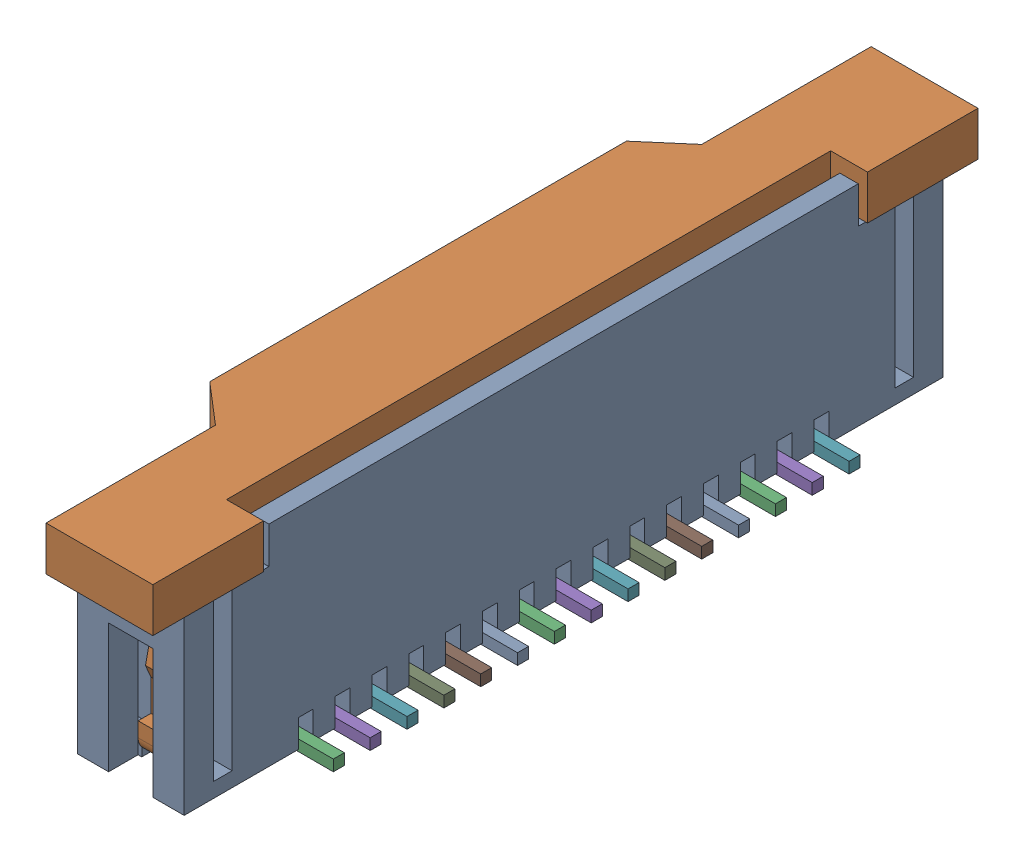
SolidWorks assembly raspberry_pi__15_pin_FFC_Connector, configuration Default. Lengths in mm.
Overall size (4.85 6 22.4).
17 component instances, 3 part files, 0 mates.
Components (placement in the parent):
- raspberry_pi__15_pin_FFC_Connector_body-1: raspberry_pi__15_pin_FFC_Connector_body [Default] at (-100.5372 19.1242 0) size (2.9 5.7 20.6)
- raspberry_pi__15_pin_FFC_Connector_locker-1: raspberry_pi__15_pin_FFC_Connector_locker [Default] at (-101.0372 23.8242 0) size (4 5.4 22.4)
- raspberry_pi__15_pin_FFC_Connector_pins-1: raspberry_pi__15_pin_FFC_Connector_pins [Default] at (-100.5372 19.1242 7.15) x (-1 0 0) z (0 0 -1) size (4.3 4.71 0.3)
- raspberry_pi__15_pin_FFC_Connector_pins-2: raspberry_pi__15_pin_FFC_Connector_pins [Default] at (-100.5372 19.1242 6.15) x (-1 0 0) z (0 0 -1) size (4.3 4.71 0.3)
- raspberry_pi__15_pin_FFC_Connector_pins-3: raspberry_pi__15_pin_FFC_Connector_pins [Default] at (-100.5372 19.1242 5.15) x (-1 0 0) z (0 0 -1) size (4.3 4.71 0.3)
- raspberry_pi__15_pin_FFC_Connector_pins-4: raspberry_pi__15_pin_FFC_Connector_pins [Default] at (-100.5372 19.1242 4.15) x (-1 0 0) z (0 0 -1) size (4.3 4.71 0.3)
- raspberry_pi__15_pin_FFC_Connector_pins-5: raspberry_pi__15_pin_FFC_Connector_pins [Default] at (-100.5372 19.1242 3.15) x (-1 0 0) z (0 0 -1) size (4.3 4.71 0.3)
- raspberry_pi__15_pin_FFC_Connector_pins-6: raspberry_pi__15_pin_FFC_Connector_pins [Default] at (-100.5372 19.1242 2.15) x (-1 0 0) z (0 0 -1) size (4.3 4.71 0.3)
- raspberry_pi__15_pin_FFC_Connector_pins-7: raspberry_pi__15_pin_FFC_Connector_pins [Default] at (-100.5372 19.1242 1.15) x (-1 0 0) z (0 0 -1) size (4.3 4.71 0.3)
- raspberry_pi__15_pin_FFC_Connector_pins-8: raspberry_pi__15_pin_FFC_Connector_pins [Default] at (-100.5372 19.1242 0.15) x (-1 0 0) z (0 0 -1) size (4.3 4.71 0.3)
- raspberry_pi__15_pin_FFC_Connector_pins-9: raspberry_pi__15_pin_FFC_Connector_pins [Default] at (-100.5372 19.1242 -0.85) x (-1 0 0) z (0 0 -1) size (4.3 4.71 0.3)
- raspberry_pi__15_pin_FFC_Connector_pins-10: raspberry_pi__15_pin_FFC_Connector_pins [Default] at (-100.5372 19.1242 -1.85) x (-1 0 0) z (0 0 -1) size (4.3 4.71 0.3)
- raspberry_pi__15_pin_FFC_Connector_pins-11: raspberry_pi__15_pin_FFC_Connector_pins [Default] at (-100.5372 19.1242 -2.85) x (-1 0 0) z (0 0 -1) size (4.3 4.71 0.3)
- raspberry_pi__15_pin_FFC_Connector_pins-12: raspberry_pi__15_pin_FFC_Connector_pins [Default] at (-100.5372 19.1242 -3.85) x (-1 0 0) z (0 0 -1) size (4.3 4.71 0.3)
- raspberry_pi__15_pin_FFC_Connector_pins-13: raspberry_pi__15_pin_FFC_Connector_pins [Default] at (-100.5372 19.1242 -4.85) x (-1 0 0) z (0 0 -1) size (4.3 4.71 0.3)
- raspberry_pi__15_pin_FFC_Connector_pins-14: raspberry_pi__15_pin_FFC_Connector_pins [Default] at (-100.5372 19.1242 -5.85) x (-1 0 0) z (0 0 -1) size (4.3 4.71 0.3)
- raspberry_pi__15_pin_FFC_Connector_pins-15: raspberry_pi__15_pin_FFC_Connector_pins [Default] at (-100.5372 19.1242 -6.85) x (-1 0 0) z (0 0 -1) size (4.3 4.71 0.3)
